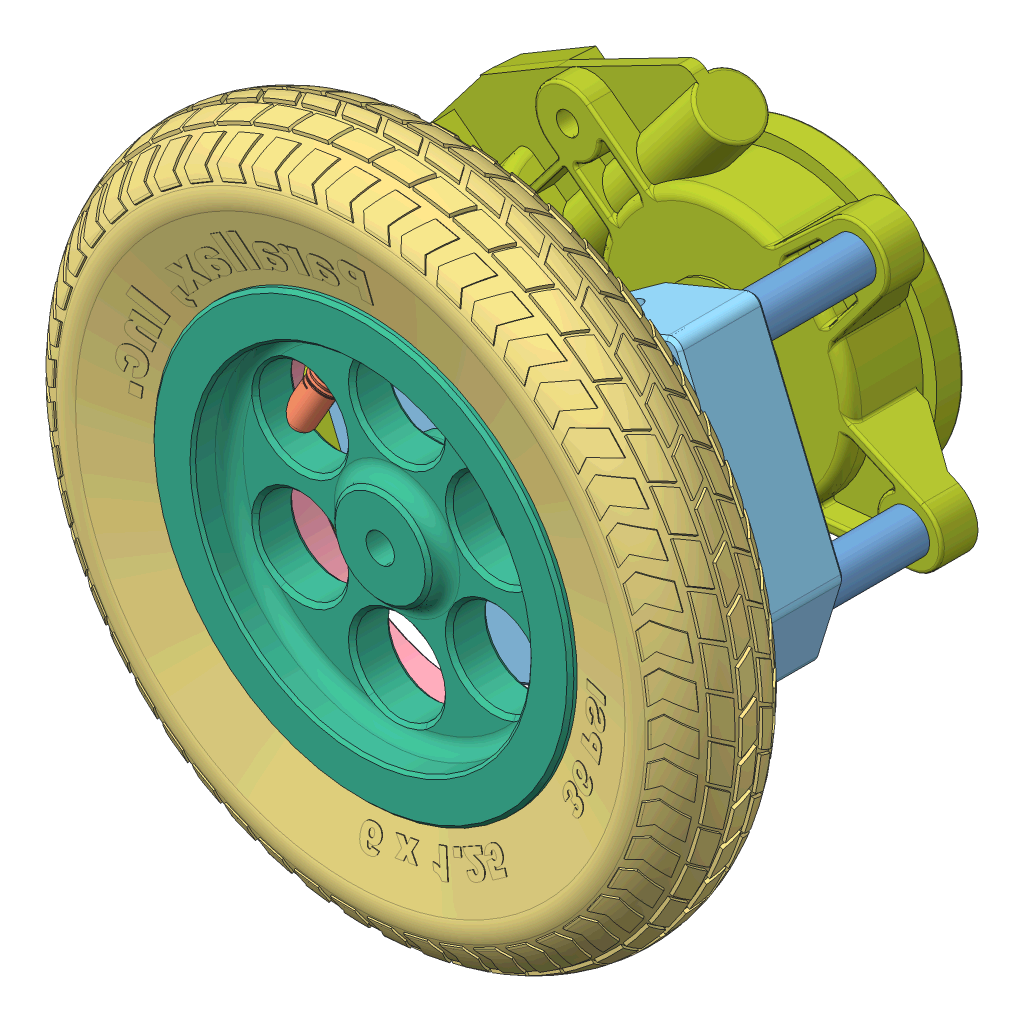
SolidWorks assembly motor_assembly_mirrored, configuration Défaut. Lengths in mm.
Overall size (205.54 165.61 108.01).
11 component instances, 8 part files, 19 mates.
Components (placement in the parent):
- Symétrie28962-28963-8-IDx1-Al-Spacer-1: Symétrie28962-28963-8-IDx1-Al-Spacer [92510A629] at (74.4961 4.4474 -122.0159) size (9.53 9.53 25.4)
- Symétrie28962-28963-Inner-Tube-1: Symétrie28962-28963-Inner-Tube [Default] at (118.947 2.3408 -65.4464) size (149.61 149.61 26.31)
- Symétrie28962-28963-Rubber-Tire-1: Symétrie28962-28963-Rubber-Tire [Default] at (118.5211 -58.6781 -63.8785) x (0.999976 -0.00698 0) z (0 0 1) size (154.71 154.78 28.25)
- Symétrie28962-28963-Wheel-Rim-Ring-Section-1: Symétrie28962-28963-Wheel-Rim-Ring-Section [Default] at (118.947 2.3408 -65.1199) size (95.25 95.25 8.25)
- Symétrie28962-Motor-Bearing-Block-2-Aluminum-1: Symétrie28962-Motor-Bearing-Block-2-Aluminum [Default] at (118.947 2.3408 -109.3159) x (-0.923728 -0.383049 0) z (-0.383049 0.923728 0) size (93.98 19.31 66.04)
- Symétrie28962-Wheel-Main-Rim-Section-AL-1: Symétrie28962-Wheel-Main-Rim-Section-AL [Default] at (118.947 2.3408 -65.1199) size (95.25 95.25 24.13)
- Symétrie750-90006-Motor12VDC-1: Symétrie750-90006-Motor12VDC [Default] at (118.877 2.1715 -156.7504) x (-0.923728 -0.383049 0) z (-0.383049 0.923728 0) size (165.94 33.59 93.96)
- SymétrieDrive Axle-34031-1: SymétrieDrive Axle-34031 [Default] at (118.947 2.3408 -131.7949) x (-0.923728 -0.383049 0) z (-0.383049 0.923728 0) size (21.59 66.67 21.59)
- Symétrie28962-28963-8-IDx1-Al-Spacer-2: Symétrie28962-28963-8-IDx1-Al-Spacer [92510A629] at (148.8629 35.2856 -122.0159) size (9.53 9.53 25.4)
- Symétrie28962-28963-8-IDx1-Al-Spacer-3: Symétrie28962-28963-8-IDx1-Al-Spacer [92510A629] at (99.5105 -37.691 -122.0159) size (9.53 9.53 25.4)
- Symétrie28962-28963-8-IDx1-Al-Spacer-4: Symétrie28962-28963-8-IDx1-Al-Spacer [92510A629] at (161.009 -12.189 -122.0159) size (9.53 9.53 25.4)
Mates (geometry in assembly coordinates):
- Coaxiale1: concentric aligned: cylinder of Symétrie28962-28963-Inner-Tube-1 through (118.947 2.3408 -65.4464) axis (0 0 1) radius 47.8634; cylinder of Symétrie28962-Wheel-Main-Rim-Section-AL-1 through (118.947 2.3408 -119.1267) axis (0 0 1) radius 43.815
- Coaxiale2: concentric aligned: circle of Symétrie28962-28963-Rubber-Tire-1; circle of Symétrie28962-Wheel-Main-Rim-Section-AL-1
- Coïncidente1: coincident anti-aligned: plane of Symétrie28962-28963-Wheel-Rim-Ring-Section-1 through (118.947 2.3408 -69.5649) normal (0 0 1); plane of Symétrie28962-Wheel-Main-Rim-Section-AL-1 through (80.847 2.3408 -69.5649) normal (0 0 -1)
- Coaxiale3: concentric aligned: circle of Symétrie28962-28963-Wheel-Rim-Ring-Section-1; circle of Symétrie28962-Wheel-Main-Rim-Section-AL-1
- Coaxiale4: concentric anti-aligned: circle of Symétrie750-90006-Motor12VDC-1; circle of SymétrieDrive Axle-34031-1
- Parallèle1: parallel anti-aligned: plane of Symétrie750-90006-Motor12VDC-1 through (116.199 -4.301 -124.1749) normal (0.383049 -0.923728 0); plane of SymétrieDrive Axle-34031-1 through (117.342 -3.7418 -124.1749) normal (-0.383049 0.923728 0)
- Coïncidente2: coincident anti-aligned: plane of Symétrie750-90006-Motor12VDC-1 through (118.877 2.1715 -124.1749) normal (0 0 1); plane of SymétrieDrive Axle-34031-1 through (116.8856 -2.6414 -124.1749) normal (0 0 -1)
- Coaxiale5: concentric aligned: cylinder of Symétrie28962-Wheel-Main-Rim-Section-AL-1 through (118.947 2.3408 -65.1199) axis (0 0 -1) radius 6.35; cylinder of SymétrieDrive Axle-34031-1 through (118.947 2.3408 -65.1199) axis (0 0 -1) radius 6.3373
- Coaxiale6: concentric aligned: cylinder of Symétrie28962-Motor-Bearing-Block-2-Aluminum-1 through (118.947 2.3408 -90.2659) axis (0 0 -1) radius 8.89; cylinder of SymétrieDrive Axle-34031-1 through (118.947 2.3408 -65.1199) axis (0 0 -1) radius 6.3373
- Coaxiale7: concentric aligned: cylinder of Symétrie28962-28963-8-IDx1-Al-Spacer-1 through (74.4961 4.4474 -134.7159) axis (0 0 1) radius 2.1082; cylinder of Symétrie28962-Motor-Bearing-Block-2-Aluminum-1 through (74.4961 4.4474 -90.2659) axis (0 0 1) radius 3
- Coaxiale8: concentric aligned: cylinder of Symétrie28962-Motor-Bearing-Block-2-Aluminum-1 through (148.8629 35.2856 -90.2659) axis (0 0 1) radius 3; cylinder of Symétrie28962-28963-8-IDx1-Al-Spacer-2 through (148.8629 35.2856 -134.7159) axis (0 0 1) radius 2.1082
- Coaxiale9: concentric aligned: cylinder of Symétrie28962-Motor-Bearing-Block-2-Aluminum-1 through (99.5105 -37.691 -90.2659) axis (0 0 1) radius 3; cylinder of Symétrie28962-28963-8-IDx1-Al-Spacer-3 through (99.5105 -37.691 -134.7159) axis (0 0 1) radius 2.1082
- Coaxiale10: concentric aligned: cylinder of Symétrie28962-Motor-Bearing-Block-2-Aluminum-1 through (161.009 -12.189 -90.2659) axis (0 0 1) radius 3; cylinder of Symétrie28962-28963-8-IDx1-Al-Spacer-4 through (161.009 -12.189 -134.7159) axis (0 0 1) radius 2.1082
- Coïncidente3: coincident anti-aligned: plane of Symétrie28962-Motor-Bearing-Block-2-Aluminum-1 through (118.947 2.3408 -109.3159) normal (0 0 -1); plane of Symétrie28962-28963-8-IDx1-Al-Spacer-2 through (148.8629 35.2856 -109.3159) normal (0 0 1)
- Coïncidente4: coincident anti-aligned: plane of Symétrie28962-Motor-Bearing-Block-2-Aluminum-1 through (118.947 2.3408 -109.3159) normal (0 0 -1); plane of Symétrie28962-28963-8-IDx1-Al-Spacer-4 through (161.009 -12.189 -109.3159) normal (0 0 1)
- Coïncidente5: coincident anti-aligned: plane of Symétrie28962-28963-8-IDx1-Al-Spacer-1 through (74.4961 4.4474 -109.3159) normal (0 0 1); plane of Symétrie28962-Motor-Bearing-Block-2-Aluminum-1 through (118.947 2.3408 -109.3159) normal (0 0 -1)
- Coïncidente6: coincident anti-aligned: plane of Symétrie28962-Motor-Bearing-Block-2-Aluminum-1 through (118.947 2.3408 -109.3159) normal (0 0 -1); plane of Symétrie28962-28963-8-IDx1-Al-Spacer-3 through (99.5105 -37.691 -109.3159) normal (0 0 1)
- Coïncidente7: coincident anti-aligned: plane of Symétrie750-90006-Motor12VDC-1 through (148.6717 35.1497 -134.7159) normal (0 0 1); plane of Symétrie28962-28963-8-IDx1-Al-Spacer-4 through (161.009 -12.189 -134.7159) normal (0 0 -1)
- Coïncidente8: coincident anti-aligned: plane of Symétrie28962-Wheel-Main-Rim-Section-AL-1 through (118.947 2.3408 -65.1199) normal (0 0 -1); plane of SymétrieDrive Axle-34031-1 through (118.947 2.3408 -65.1199) normal (0 0 1)
